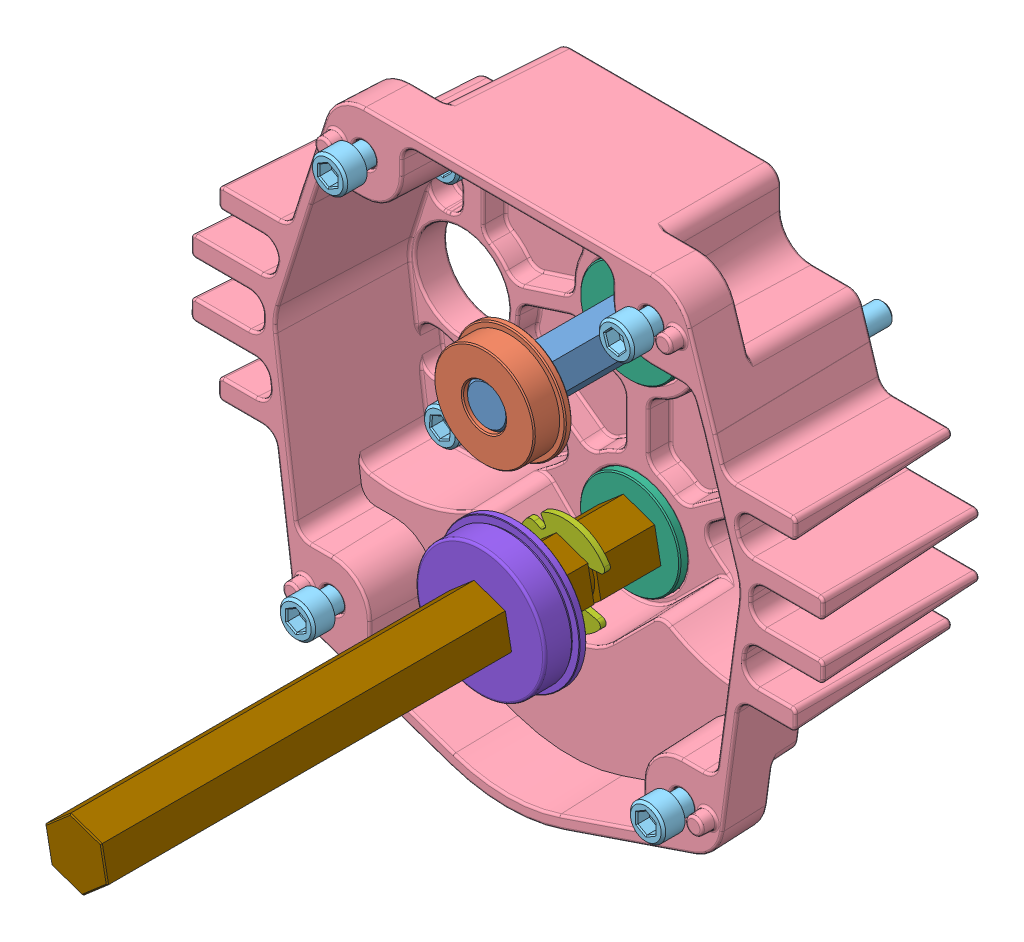
SolidWorks assembly ToughboxMini, configuration Default. Lengths in mm.
Overall size (140.05 118.73 142.29).
20 component instances, 9 part files, 0 mates.
Components (placement in the parent):
- TBMiniSmallHexShaft-1: TBMiniSmallHexShaft [Default] at (-127.8104 29.3671 -52.3959) x (-0.59657 -0.802561 0) z (-0.802561 0.59657 0) size (11 38.23 9.52)
- Bearing_FR6ZZ-1: Bearing_FR6ZZ [Default] at (-96.247 60.278 -52.5991) x (-0.893862 0.448342 0) z (0 0 1) size (24.69 24.69 7.16)
- NylockNut_10-32-1: NylockNut_10-32 [Default] at (-129.8464 -8.0737 -56.3837) x (0.501678 0.865055 0) z (0 0 -1) size (9.53 11 5.96)
- NylockNut_10-32-2: NylockNut_10-32 [Default] at (-59.2462 80.7349 -56.3837) x (0.999999 -0.001296 0) z (0 0 -1) size (9.53 11 5.96)
- NylockNut_10-32-3: NylockNut_10-32 [Default] at (-122.7461 80.8172 -56.3837) x (0.500567 0.865698 0) z (0 0 -1) size (9.53 11 5.96)
- NylockNut_10-32-4: NylockNut_10-32 [Default] at (-52.3764 -8.1741 -56.3837) x (-0.501678 -0.865055 0) z (0 0 -1) size (9.53 11 5.96)
- TBMiniHousing-1: TBMiniHousing [Default] at (-91.0876 10.1882 -86.3557) x (0.999999 -0.001296 0) z (0 0 1) size (139.9 118.55 41.62)
- Screw_SHCS_10-32x0.625-1: Screw_SHCS_10-32x0.625 [Default] at (-52.2832 63.7078 -74.4685) x (-0.564778 -0.825243 0) z (-0.825243 0.564778 0) size (7.82 20.65 7.82)
- Screw_SHCS_10-32x0.625-2: Screw_SHCS_10-32x0.625 [Default] at (-122.7461 80.8172 -42.5915) x (0.507484 -0.861661 0) z (-0.861661 -0.507484 0) size (7.82 20.65 7.82)
- Screw_SHCS_10-32x0.625-3: Screw_SHCS_10-32x0.625 [Default] at (-52.3764 -8.1741 -42.5915) x (0.507484 -0.861661 0) z (-0.861661 -0.507484 0) size (7.82 20.65 7.82)
- Screw_SHCS_10-32x0.625-4: Screw_SHCS_10-32x0.625 [Default] at (-129.8464 -8.0737 -42.5915) x (0.507484 -0.861661 0) z (-0.861661 -0.507484 0) size (7.82 20.65 7.82)
- Screw_SHCS_10-32x0.625-5: Screw_SHCS_10-32x0.625 [Default] at (-59.2462 80.7349 -42.5915) x (0.740711 -0.671824 0) z (-0.671824 -0.740711 0) size (7.82 20.65 7.82)
- Screw_SHCS_10-32x0.625-6: Screw_SHCS_10-32x0.625 [Default] at (-52.3491 12.9079 -74.4685) x (-0.564778 -0.825243 0) z (-0.825243 0.564778 0) size (7.82 20.65 7.82)
- Screw_SHCS_10-32x0.625-7: Screw_SHCS_10-32x0.625 [Default] at (-129.7532 63.8083 -74.4685) x (-0.966277 -0.257503 0) z (-0.257503 0.966277 0) size (7.82 20.65 7.82)
- Screw_SHCS_10-32x0.625-8: Screw_SHCS_10-32x0.625 [Default] at (-129.819 13.0083 -74.4685) x (-0.99652 0.083357 0) z (0.083357 0.99652 0) size (7.82 20.65 7.82)
- Bearing_R6ZZ-1: Bearing_R6ZZ [Default] at (-91.0349 50.9043 -84.8317) x (0.958138 -0.286306 0) z (0 0 1) size (22.23 22.23 7.11)
- Bearing_R6ZZ-2: Bearing_R6ZZ [Default] at (-91.0876 10.1882 -84.8317) x (-0.661529 0.74992 0) z (0 0 1) size (22.23 22.23 7.11)
- ExternalKlipring-1: ExternalKlipring [Default] at (-91.0876 10.1882 -64.4355) x (0.996411 -0.084651 0) z (0 0 1) size (19.07 20.96 1.27)
- Bearing_Hex_FR8ZZ-1: Bearing_Hex_FR8ZZ [Default] at (-91.0876 10.1882 -44.6717) x (0.188693 -0.982036 0) z (0 0 -1) size (31.12 31.12 7.93)
- TBMiniHexOutputShaft-1: TBMiniHexOutputShaft [Default] at (-100.2289 -30.5762 -52.3197) x (0.188693 -0.982036 0) z (-0.982036 -0.188693 0) size (14.66 142.29 12.7)
